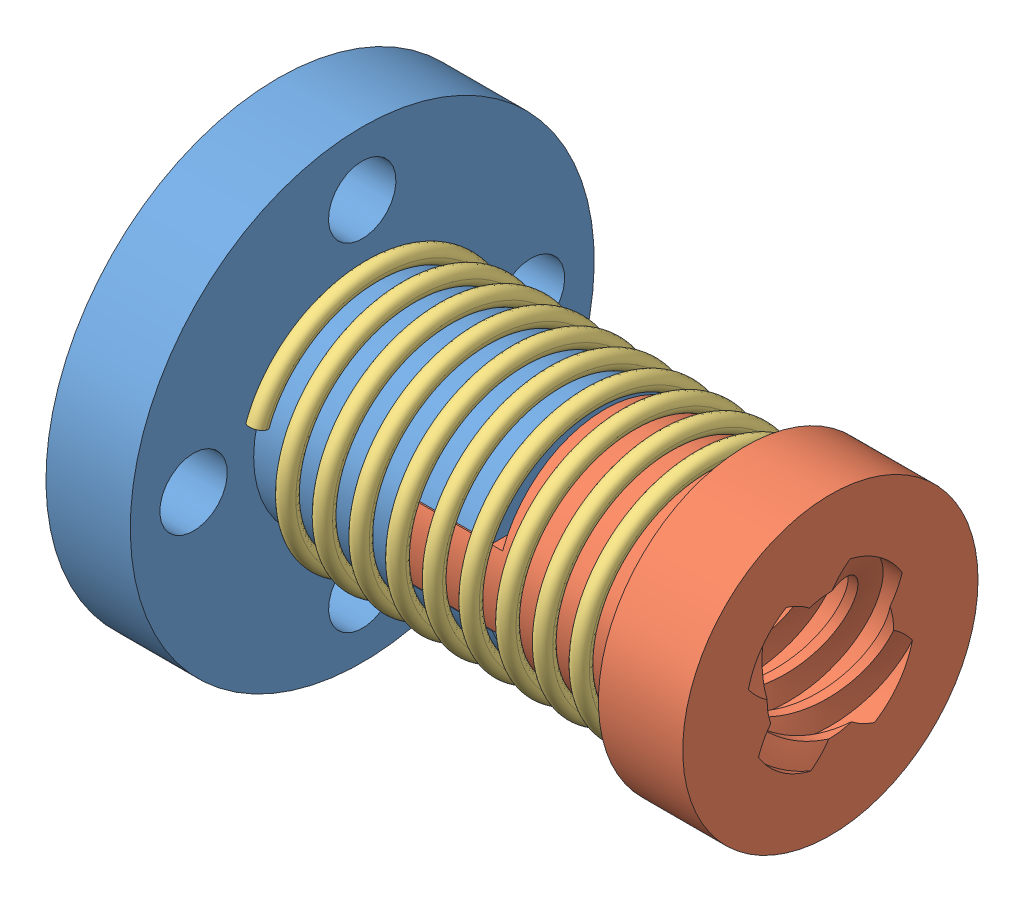
SolidWorks assembly Spring Nut, configuration Default. Lengths in mm.
Overall size (26.6 22 22).
3 component instances, 3 part files, 5 mates.
Components (placement in the parent):
- T8 Lead screw brass nut 1-1: T8 Lead screw brass nut 1 [Default] at (-11.2 0 0) x (-1 0 0) z (0 -0.000197 1) size (15.4 22 22)
- T8 Lead screw brass nut 2-1: T8 Lead screw brass nut 2 [Default] at origin size (15.41 14 14)
- Spring D10.8-1: Spring D10.8 [Default] at (-4.4 0 0) x (-1 0 0) z (0 0.95716 -0.289558) size (18.25 12.02 12)
Mates (geometry in assembly coordinates):
- Concentric1: concentric aligned: cylinder of T8 Lead screw brass nut 1-1 through (-26.2 0 0) axis (1 0 0) radius 11; cylinder of T8 Lead screw brass nut 2-1 through (-4 0 0) axis (1 0 0) radius 7
- Distance1: distance = 18.2 mm anti-aligned: plane of T8 Lead screw brass nut 1-1 through (-22.2 11.1298 11.1342) normal (1 0 0); plane of T8 Lead screw brass nut 2-1 through (-4 -7.084 -7.084) normal (-1 0 0)
- Concentric2: concentric anti-aligned: circle of Lead Screw T8X8X400-1; cylinder of T8 Lead screw brass nut 1-1 through (-26.2 0 0) axis (1 0 0) radius 11
- Lock1: lock: unknown of T8 Lead screw brass nut 1-1; unknown of Spring D10.8-1
- Coincident1: coordinate: point of T8 Lead screw brass nut 2-1
